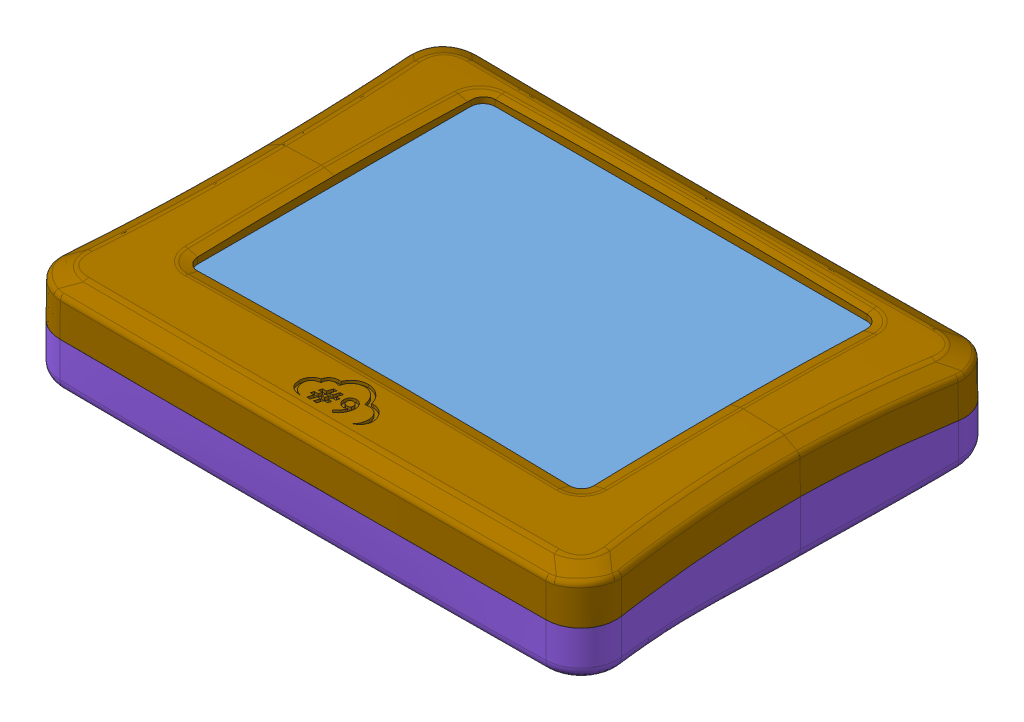
SolidWorks assembly Model-221-08-2015, configuration Stand Close position. Lengths in mm.
Overall size (92.49 19.12 72.21).
25 component instances, 16 part files, 50 mates.
Components (placement in the parent):
- Electronics21-08-2015-1: Electronics21-08-2015 [Default] at (-1.6 -3.7751 -1) x (0 0 -1) z (1 0 0) size (63.25 16.29 82.33)
  - display21-08-2015-1: display21-08-2015 [Default] at (-1 0.5751 0) size (63.25 7.23 81.89)
  - BIVAR LIGHTPIPE PLP2-12521-08-2015-1: BIVAR LIGHTPIPE PLP2-12521-08-2015 [Default] at (15.3149 -7.9169 38.0247) x (0.952304 0 -0.305152) z (0 1 0) size (3.35 3.46 9.96)
  - micro-usb21-08-2015-1: micro-usb21-08-2015 [Default] at (-0.6 -5.7049 6) x (0 0 -1) z (0 -1 0) size (7.98 2.76 5.43)
  - b3u-3100p-b21-08-2015-1: b3u-3100p-b21-08-2015 [Default] at (25.0639 -2.9504 -22.73) x (0 0 1) z (1 0 0) size (4.67 1.98 4.49)
  - b3u-3100p-b21-08-2015-2: b3u-3100p-b21-08-2015 [Default] at (25.0639 -2.9504 -12.4419) x (0 0 1) z (1 0 0) size (4.67 1.98 4.49)
  - Copy of Copy of Wifi-chip^Electronics21-08-2015-1: Copy of Copy of Wifi-chip^Electronics21-08-2015 [Default] at (-2.5 -2.8549 5.8984) x (0 0 1) z (1 0 0) size (35 2.3 25) (virtual)
  - 3 COLOR LED21-08-2015-1: 3 COLOR LED21-08-2015 [Default] at (15.2723 -2.8549 38.0029) x (0 0 1) z (0 -1 0) size (3.2 2.6 1.1)
  - Battery-holder21-08-2015-1: Battery-holder21-08-2015 [Default] at (0 -1.3481 2) size (46.5 5.9 41.87)
- Monitor-holder21-08-2015-1: Monitor-holder21-08-2015 [Default] at (0.0231 -42.088 27.868) x (-0.999993 -0.003136 -0.002099) z (0.003149 -0.999975 -0.006363) (hidden)
- Back21-08-2015-1: Back21-08-2015 [Default] at origin
- Front-part-1: Front-part [Default] at origin
- battery21-08-2015-1: battery21-08-2015 [Default] at (-22.1 -11.63 0) x (0 0 1) z (-1 0 0)
- Push-button-1: Push-button [Default] at (-13.8185 -7.5 -30.4965) x (1 0 0) z (0 1 0)
- Push-button-2: Push-button [Default] at (-24.1815 -7.5 -30.4892) x (0.999727 0.023382 0) z (-0.023382 0.999727 0)
- 93365A11021-08-2015-5: 93365A11021-08-2015 [93365A110] at (-33.6 -4.25 32.3412) x (-0.870136 0 -0.492811) z (-0.492811 0 0.870136)
- 93365A11021-08-2015-6: 93365A11021-08-2015 [93365A110] at (-40.75 -11 32.5) x (0.837169 0 0.546944) z (0.546944 0 -0.837169)
- 93365A11021-08-2015-7: 93365A11021-08-2015 [93365A110] at (30.4 -1.3301 32.3412) x (0.870136 0 -0.492811) z (0.492811 0 0.870136)
- 93365A11021-08-2015-8: 93365A11021-08-2015 [93365A110] at (37.55 -8.0801 32.5) x (-0.837169 0 0.546944) z (-0.546944 0 -0.837169)
- Kickstand-121-08-2015-2: Kickstand-121-08-2015 [Default] at (-0.0921 0 0)
- pan cross head_ai-1: pan cross head_ai [CR-PHMS 0.086-56x0.188x0.188-S] at (-40.75 -14.1748 32.5) x (0 1 0) z (-0.546944 0 0.837169)
- pan cross head_ai-5: pan cross head_ai [CR-PHMS 0.086-56x0.188x0.188-S] at (39.1648 -14.1748 32.885) x (0 1 0) z (-0.546944 0 0.837169)
- pan cross head_ai-8: pan cross head_ai [CR-PHMS 0.086-56x0.188x0.188-S] at (30.4 -8.2048 32.3412) x (0 1 0) z (-0.546944 0 0.837169)
- pan cross head_ai-9: pan cross head_ai [CR-PHMS 0.086-56x0.188x0.188-S] at (-33.6 -8.2048 32.3412) x (0 1 0) z (-0.546944 0 0.837169)
- 91585A01421-08-2015-1: 91585A01421-08-2015 [91585A014] at (22.0407 -13.5075 -7.6197) x (1 0 0) z (0 0.497089 0.8677)
Mates (geometry in assembly coordinates):
- Concentric1: concentric aligned: cylinder of ? through (-26.532 -11.6847 -35.7203) axis (0 0 1) radius 3.1348; cylinder of ? through (-26.532 -11.6847 -35.5379) axis (0 0 1) radius 3.5
- Coincident1: coordinate: unknown of ?
- Concentric2: concentric aligned: cylinder of ? through (-16.5596 -11.6847 -35.5379) axis (0 0 1) radius 3.5; cylinder of ? through (-16.5596 -11.6847 -35.7203) axis (0 0 1) radius 3.1348
- Concentric3: concentric aligned: cylinder of ? through (-6.5871 -10.4879 -35.0789) axis (0 0 1) radius 3.5; cylinder of ? through (-6.5871 -10.4879 -34.5834) axis (0 0 1) radius 3.1348
- Concentric4: concentric aligned: cylinder of ? through (3.3854 -10.4879 -35.0789) axis (0 0 1) radius 3.5; cylinder of ? through (3.3854 -10.4879 -34.5834) axis (0 0 1) radius 3.1348
- Coincident3: coincident aligned: plane of ? through (-26.532 -11.6847 -33.7203) normal (0 0 -1); plane of ? through (-16.5596 -11.6847 -33.7203) normal (0 0 -1)
- Coincident4: coincident aligned: plane of ? through (-26.532 -10.4879 -32.5834) normal (0 0 -1); plane of ? through (-6.5871 -10.4879 -32.5834) normal (0 0 -1)
- Coincident5: coincident aligned: plane of ? through (-26.532 -10.4879 -32.5834) normal (0 0 -1); plane of ? through (3.3854 -10.4879 -32.5834) normal (0 0 -1)
- Parallel1: parallel anti-aligned: plane of ? through (-26.532 -11.6847 -33.7203) normal (0 -1 0); plane of assembly through (0 0 0) normal (0 1 0)
- Concentric7: concentric aligned: cylinder of ? through (-1557.1401 499949.2125 -5152.1837) axis (0.003114 -0.999942 0.010304) radius 4; cylinder of Monitor-holder21-08-2015-1 through (0.1024 -48.8165 0.17) axis (0.003114 -0.999942 0.010304) radius 4.25
- Coincident16: coordinate: unknown of ?
- Coincident17: coordinate: unknown of ?
- Coincident25: coincident aligned: plane of ? through (35.8727 -56.5448 15.7708) normal (0.003114 -0.999942 0.010304); plane of Monitor-holder21-08-2015-1 through (0.1273 -56.816 0.2524) normal (0.003114 -0.999942 0.010304)
- Concentric9: concentric aligned: cylinder of ? through (-13.8185 -7.5 -32.2107) axis (0 0 1) radius 3; cylinder of Push-button-1 through (-13.8185 -7.5 -31.7326) axis (0 0 1) radius 2.975
- Parallel2: parallel aligned: plane of Push-button-1; plane of assembly through (0 0 0) normal (1 0 0)
- Concentric10: concentric: cylinder of ? through (-24.1815 -7.5 -32.2107) axis (0 0 1) radius 3; sphere of Push-button-2
- Coincident42: coincident anti-aligned: plane of ? through (-24.1815 -7.5 -29.45) normal (0 0 1); plane of Push-button-2 through (-24.1114 -10.4992 -29.45) normal (0 0 -1)
- Concentric12: concentric anti-aligned: cylinder of ? through (-39.9507 -23.5289 30) axis (0 1 0) radius 3; cylinder of ? through (-39.9507 -39.432 30) axis (0 -1 0) radius 2.7813
- Concentric13: concentric aligned: cylinder of ? through (-40.75 500000 32.5) axis (0 -1 0) radius 1.5; cylinder of 93365A11021-08-2015-6 through (-40.75 -8.079 32.5) axis (0 -1 0) radius 1.4986
- Coincident45: coincident aligned: plane of ? through (-40.75 -11 32.5) normal (0 -1 0); plane of 93365A11021-08-2015-6 through (-40.75 -11 32.5) normal (0 -1 0)
- Concentric14: concentric anti-aligned: cylinder of ? through (-33.6 -13.4813 32.3412) axis (0 1 0) radius 1.4986; cylinder of 93365A11021-08-2015-5 through (-33.6 -1.329 32.3412) axis (0 -1 0) radius 1.4986
- Coincident47: coincident anti-aligned: plane of Electronics21-08-2015-1/display21-08-2015-1 through (-1.6 -3.2 0) normal (0 0 -1); plane of assembly through (0 0 0) normal (0 0 1)
- Distance32: distance = 1.6 mm aligned: plane of ? through (0 0 0) normal (1 0 0); plane of Electronics21-08-2015-1/display21-08-2015-1 through (-1.6 -3.2 0) normal (1 0 0)
- Concentric15: concentric aligned: cylinder of Electronics21-08-2015-1/display21-08-2015-1 through (-32 -6.0567 31) axis (0 -1 0) radius 1.52; cylinder of ? through (-32 -34.6615 31) axis (0 -1 0) radius 2.1209
- Coincident55: coincident anti-aligned: plane of Electronics21-08-2015-1/display21-08-2015-1 through (0 -7.6867 0) normal (0 -1 0); plane of ? through (-33.0922 -7.6867 31) normal (0 1 0)
- Distance28: distance = 22.1 mm anti-aligned: plane of battery21-08-2015-1 through (-22.1 -11.63 0) normal (-1 0 0); plane of assembly through (0 0 0) normal (1 0 0)
- Coincident63: coincident aligned: plane of battery21-08-2015-1 through (-22.1 -11.63 0) normal (0 0 1); plane of assembly through (0 0 0) normal (0 0 1)
- Distance30: distance = 2 mm anti-aligned: plane of battery21-08-2015-1 through (-22.1 -8.63 0) normal (0 1 0); plane of Electronics21-08-2015-1/display21-08-2015-1 through (-1.6 -6.63 0) normal (0 -1 0)
- Coincident58: coincident anti-aligned: plane of Electronics21-08-2015-1/display21-08-2015-1 through (0 -7.6867 0) normal (0 -1 0); plane of ? through (-29.4866 -7.6867 24.2678) normal (0 1 0)
- Concentric22: concentric aligned: cylinder of ? through (39.9507 -23.5289 30) axis (0 1 0) radius 2.51; cylinder of ? through (39.9507 9.4229 30) axis (0 1 0) radius 2.1209
- Concentric23: concentric anti-aligned: cylinder of ? through (39.9507 -23.5289 -30) axis (0 1 0) radius 2.51; cylinder of ? through (39.9507 9.8689 -30) axis (0 -1 0) radius 2.1209
- Coincident61: coincident anti-aligned: plane of Electronics21-08-2015-1/display21-08-2015-1 through (-1.6 -6.63 0) normal (0 -1 0); plane of pan cross head_ai-8 through (29.4856 -6.63 31.7438) normal (0 1 0)
- Coincident62: coincident anti-aligned: plane of Electronics21-08-2015-1/display21-08-2015-1 through (-1.6 -6.63 0) normal (0 -1 0); plane of pan cross head_ai-9 through (-34.5144 -6.63 31.7438) normal (0 1 0)
- Concentric28: concentric aligned: cylinder of pan cross head_ai-8 through (30.4 -33.6048 32.3412) axis (0 -1 0) radius 2.1209; cylinder of Electronics21-08-2015-1/display21-08-2015-1 through (30.4 -5 32.3412) axis (0 -1 0) radius 1.52
- Concentric29: concentric aligned: cylinder of pan cross head_ai-9 through (-33.6 -33.6048 32.3412) axis (0 -1 0) radius 2.1209; cylinder of Electronics21-08-2015-1/display21-08-2015-1 through (-33.6 -5 32.3412) axis (0 -1 0) radius 1.52
- Distance31: distance = 5 mm aligned: plane of Electronics21-08-2015-1/display21-08-2015-1 through (-1.6 -5 0) normal (0 1 0); plane of ? through (0 0 0) normal (0 1 0)
- Coincident64: coincident anti-aligned: plane of Electronics21-08-2015-1/Copy of Copy of Wifi-chip^Electronics21-08-2015-1 through (5.8984 -6.23 1.5) normal (0 -1 0); plane of ? through (37.8803 -6.23 -24.3784) normal (0 1 0)
- Concentric30: concentric aligned: cylinder of Electronics21-08-2015-1/display21-08-2015-1 through (38.7946 -3.8 -23.7811) axis (0 -1 0) radius 1.52; cylinder of ? through (38.7946 -33.2048 -23.7811) axis (0 -1 0) radius 2.1209
- Coincident65: coincident anti-aligned: plane of Electronics21-08-2015-1/display21-08-2015-1 through (0 -3.8 0) normal (0 1 0); plane of ? through (38.7946 -3.8 -23.7811) normal (0 -1 0)
- Concentric31: concentric aligned: cylinder of ? through (38.7946 -33.2048 -23.7811) axis (0 -1 0) radius 2.1209; cylinder of ? through (38.7946 -0.879 -23.7811) axis (0 -1 0) radius 1.4986
- Coincident66: coincident aligned: plane of ? through (38.7946 -3.8 -23.7811) normal (0 -1 0); plane of ? through (-42.6085 -3.8 -25.1498) normal (0 -1 0)
- Concentric32: concentric aligned: cylinder of ? through (-42.6085 -0.879 -25.1498) axis (0 -1 0) radius 1.4986; cylinder of ? through (-42.6085 -32.4048 -25.1498) axis (0 -1 0) radius 2.1209
- Coincident67: coincident anti-aligned: plane of Electronics21-08-2015-1/display21-08-2015-1 through (0 -5.43 0) normal (0 -1 0); plane of ? through (-43.5228 -5.43 -25.7472) normal (0 1 0)
- Coincident68: coincident anti-aligned: plane of ? through (40.75 -12.6 32.5) normal (0 -1 0); plane of pan cross head_ai-5 through (38.2504 -12.6 32.2876) normal (0 1 0)
- Coincident69: coincident anti-aligned: plane of ? through (-40.75 -12.6 32.5) normal (0 -1 0); plane of pan cross head_ai-1 through (-41.6644 -12.6 31.9026) normal (0 1 0)
- Concentric33: concentric anti-aligned: cylinder of Back21-08-2015-1 through (-40.75 -17.9646 32.5) axis (0 1 0) radius 2.9986; cylinder of pan cross head_ai-1 through (-40.75 -39.5748 32.5) axis (0 -1 0) radius 2.1209
- Concentric34: concentric aligned: cylinder of Back21-08-2015-1 through (12.809 -13.5075 -7.6197) axis (1 0 0) radius 0.75; cylinder of Kickstand-121-08-2015-2 through (13.682 -13.5075 -7.6197) axis (1 0 0) radius 1
- Concentric35: concentric aligned: cylinder of Kickstand-121-08-2015-2 through (13.682 -13.5075 -7.6197) axis (1 0 0) radius 1; cylinder of 91585A01421-08-2015-1 through (12.0407 -13.5075 -7.6197) axis (1 0 0) radius 0.75
- Angle1: planar angle = 0.925025 rad anti-aligned: plane of Back21-08-2015-1 through (20.3046 -13.96 28.1222) normal (0 -1 0); plane of Kickstand-121-08-2015-2
- Coincident70: coincident anti-aligned: plane of Back21-08-2015-1 through (22.8046 -13.96 28.1222) normal (0 -1 0); plane of Kickstand-121-08-2015-2 through (27.7213 -13.96 28.1222) normal (0 1 0)
